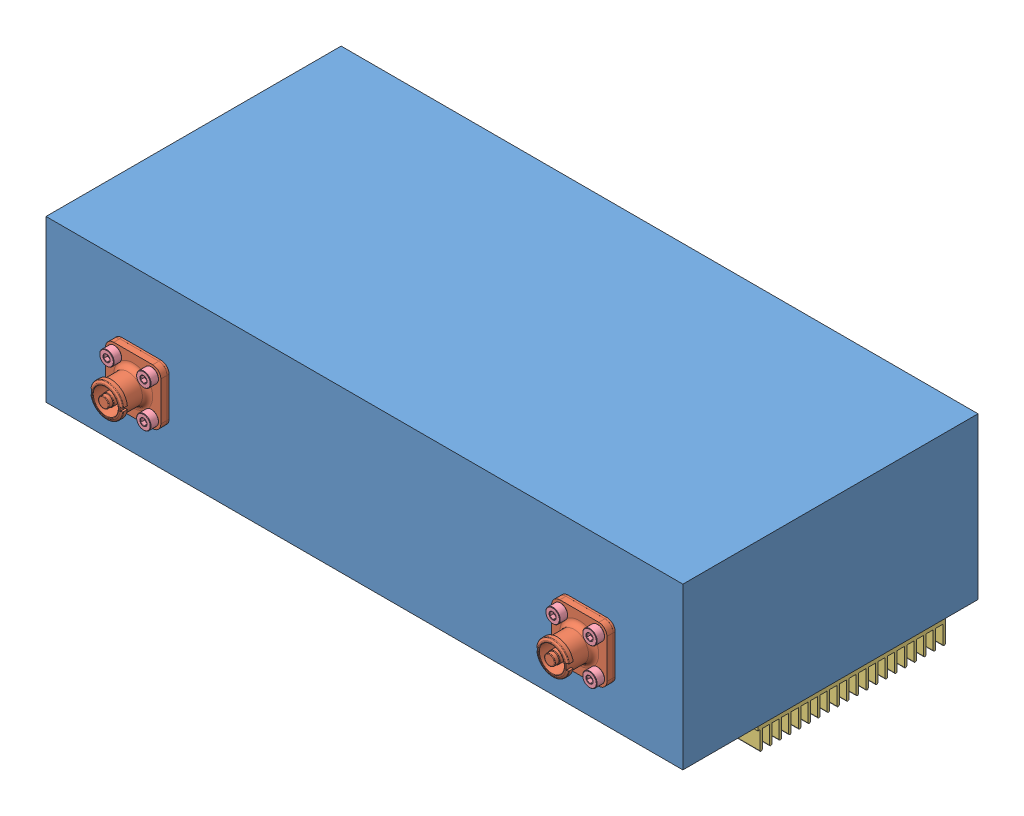
SolidWorks assembly AC-A0203-AA-Subpack Fixture Assembly, configuration Default. Lengths in mm.
Overall size (310.64 89.69 162.45).
12 component instances, 4 part files, 11 mates.
Components (placement in the parent):
- AC-X0060-AA-Subpack Case Body-1: AC-X0060-AA-Subpack Case Body [Default] at origin size (310.64 78.49 143.94)
- AC-00090-AA-Surlock Plus Maintenance Receptacles-1: AC-00090-AA-Surlock Plus Maintenance Receptacles [Default] at (108.7882 -6.8834 160.4468) x (0 0 -1) z (-1 0 0) size (38.58 27 27)
- AC-00090-AA-Surlock Plus Maintenance Receptacles-2: AC-00090-AA-Surlock Plus Maintenance Receptacles [Default] at (-108.7882 -6.8834 160.4468) x (0 0 -1) z (1 0 0) size (38.58 27 27)
- AC-00061-AA-Subpack Heatsink-1: AC-00061-AA-Subpack Heatsink [4.016lg] at (-174.9425 -37.973 14.8628) x (0 0 1) z (0 1 0) size (91.44 310.51 11.2)
- BR-Black Oxide C12.9 SHCS, M4x0.7-8 (91290A140)-1: BR-Black Oxide C12.9 SHCS, M4x0.7-8 (91290A140) [91290A140] at (-117.7882 -15.8834 145.9468) size (7 7 12.17)
- BR-Black Oxide C12.9 SHCS, M4x0.7-8 (91290A140)-2: BR-Black Oxide C12.9 SHCS, M4x0.7-8 (91290A140) [91290A140] at (-117.7882 2.1166 145.9468) x (-1 0 0) z (0 0 1) size (7 7 12.17)
- BR-Black Oxide C12.9 SHCS, M4x0.7-8 (91290A140)-3: BR-Black Oxide C12.9 SHCS, M4x0.7-8 (91290A140) [91290A140] at (-99.7882 -15.8834 145.9468) size (7 7 12.17)
- BR-Black Oxide C12.9 SHCS, M4x0.7-8 (91290A140)-4: BR-Black Oxide C12.9 SHCS, M4x0.7-8 (91290A140) [91290A140] at (-99.7882 2.1166 145.9468) x (-1 0 0) z (0 0 1) size (7 7 12.17)
- BR-Black Oxide C12.9 SHCS, M4x0.7-8 (91290A140)-5: BR-Black Oxide C12.9 SHCS, M4x0.7-8 (91290A140) [91290A140] at (99.7882 2.1166 145.9468) x (-1 0 0) z (0 0 1) size (7 7 12.17)
- BR-Black Oxide C12.9 SHCS, M4x0.7-8 (91290A140)-6: BR-Black Oxide C12.9 SHCS, M4x0.7-8 (91290A140) [91290A140] at (117.7882 2.1166 145.9468) x (-1 0 0) z (0 0 1) size (7 7 12.17)
- BR-Black Oxide C12.9 SHCS, M4x0.7-8 (91290A140)-7: BR-Black Oxide C12.9 SHCS, M4x0.7-8 (91290A140) [91290A140] at (117.7882 -15.8834 145.9468) size (7 7 12.17)
- BR-Black Oxide C12.9 SHCS, M4x0.7-8 (91290A140)-8: BR-Black Oxide C12.9 SHCS, M4x0.7-8 (91290A140) [91290A140] at (99.7882 -15.8834 145.9468) size (7 7 12.17)
Mates (geometry in assembly coordinates):
- Coincident2: coincident aligned: plane of AC-X0060-AA-Subpack Case Body-1 through (0 0 0) normal (0 0 1)
- Coincident3: coincident aligned: plane of AC-X0060-AA-Subpack Case Body-1 through (0 0 0) normal (0 1 0)
- Coincident4: coincident aligned: plane of AC-X0060-AA-Subpack Case Body-1 through (0 0 0) normal (1 0 0)
- Concentric1: concentric anti-aligned: cylinder of AC-X0060-AA-Subpack Case Body-1 through (108.7882 -6.8834 118.5418) axis (0 0 1) radius 6.985; cylinder of AC-00040-AA-Surlock Plus Receptacle-1 through (108.7882 -6.8834 146.4468) axis (0 0 -1) radius 7
- Coincident5: coincident anti-aligned: plane of AC-X0060-AA-Subpack Case Body-1 through (0 0 143.9418) normal (0 0 1); plane of AC-00040-AA-Surlock Plus Receptacle-1 through (108.7882 -6.8834 143.9418) normal (0 0 -1)
- Distance1: distance = 15.875 mm aligned: plane of AC-00061-AA-Subpack Heatsink-1 through (155.2575 -41.148 15.875) normal (0 0 -1); plane of AC-X0060-AA-Subpack Case Body-1 through (0 0 0) normal (0 0 -1)
- Width1: width anti-aligned: plane of AC-X0060-AA-Subpack Case Body-1 through (-155.321 39.243 143.9418) normal (-1 0 0); plane of AC-X0060-AA-Subpack Case Body-1 through (155.321 39.243 143.9418) normal (1 0 0); plane of AC-00061-AA-Subpack Heatsink-1 through (155.2575 -37.973 14.8628) normal (1 0 0); plane of AC-00061-AA-Subpack Heatsink-1 through (-155.2575 -50.4444 15.875) normal (-1 0 0)
- Coincident7: coincident anti-aligned: plane of AC-X0060-AA-Subpack Case Body-1 through (-155.321 -39.243 143.9418) normal (0 -1 0); plane of AC-00061-AA-Subpack Heatsink-1 through (-174.9425 -39.243 14.8628) normal (0 1 0)
- Parallel1: parallel aligned: plane of AC-X0060-AA-Subpack Case Body-1 through (-155.321 -39.243 143.9418) normal (0 -1 0); plane of AC-00041-AA-Surlock Maintenance Receptable-1 through (95.2882 -20.3834 146.4468) normal (0 -1 0)
- Concentric2: concentric aligned: cylinder of AC-00041-AA-Surlock Maintenance Receptable-2 through (-117.7882 -15.8834 148.4468) axis (0 0 -1) radius 2.1; cylinder of BR-Black Oxide C12.9 SHCS, M4x0.7-8 (91290A140)-1 through (-117.7882 -15.8834 139.9468) axis (0 0 -1) radius 2
- Coincident8: coincident anti-aligned: plane of AC-00041-AA-Surlock Maintenance Receptable-2 through (-108.7882 -6.8834 147.9468) normal (0 0 1); plane of BR-Black Oxide C12.9 SHCS, M4x0.7-8 (91290A140)-1 through (-117.7882 -12.5834 147.9468) normal (0 0 -1)
